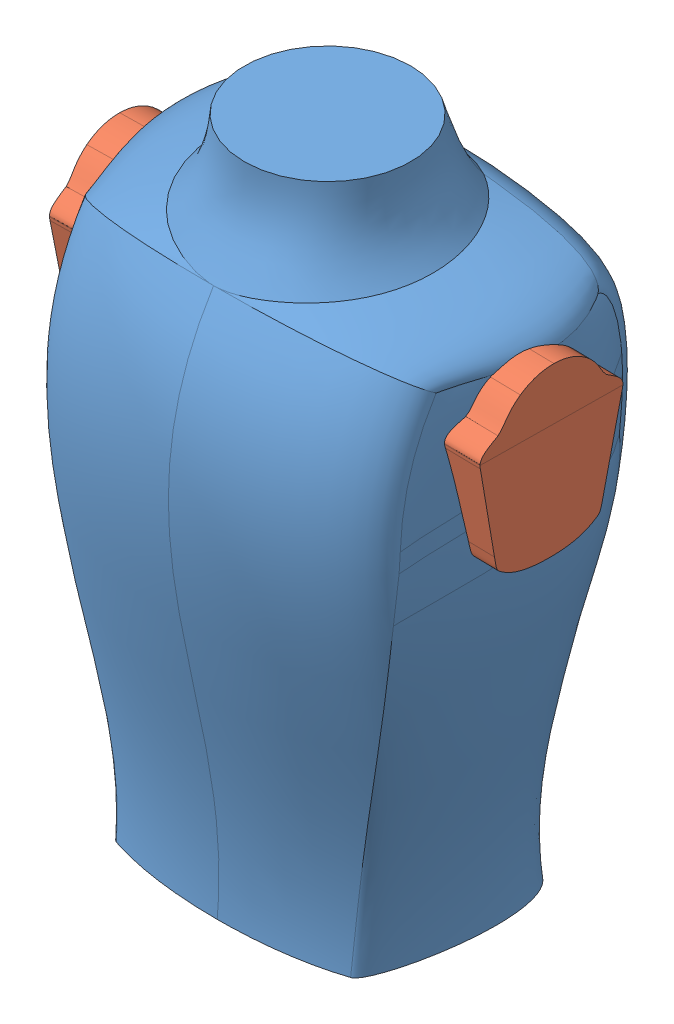
SolidWorks assembly BUSTO+SPALLE, configuration Default. Lengths in mm.
Overall size (588.02 886.55 414.62).
2 component instances, 2 part files, 2 mates.
Components (placement in the parent):
- BustoDEF-1: BustoDEF [Default] at (-31.4963 -2.4068 882.1936) size (588.02 886.55 414.62)
- Spalle-1: Spalle [Default] at (-31.4963 5.4567 883.7602) x (1 0 0) z (0 0.01153 0.999934) size (574.68 226.16 189.16)
Mates (geometry in assembly coordinates):
- Coincident3: coincident aligned: plane of BustoDEF-1 through (-31.4963 -2.4068 882.1936) normal (1 0 0); plane of Spalle-1 through (-31.4963 5.4567 883.7602) normal (1 0 0)
- Coincident7: coincident: line of BustoDEF-1 through (-284.4399 149.6555 871.5569) axis (1 0 0); point of Spalle-1
